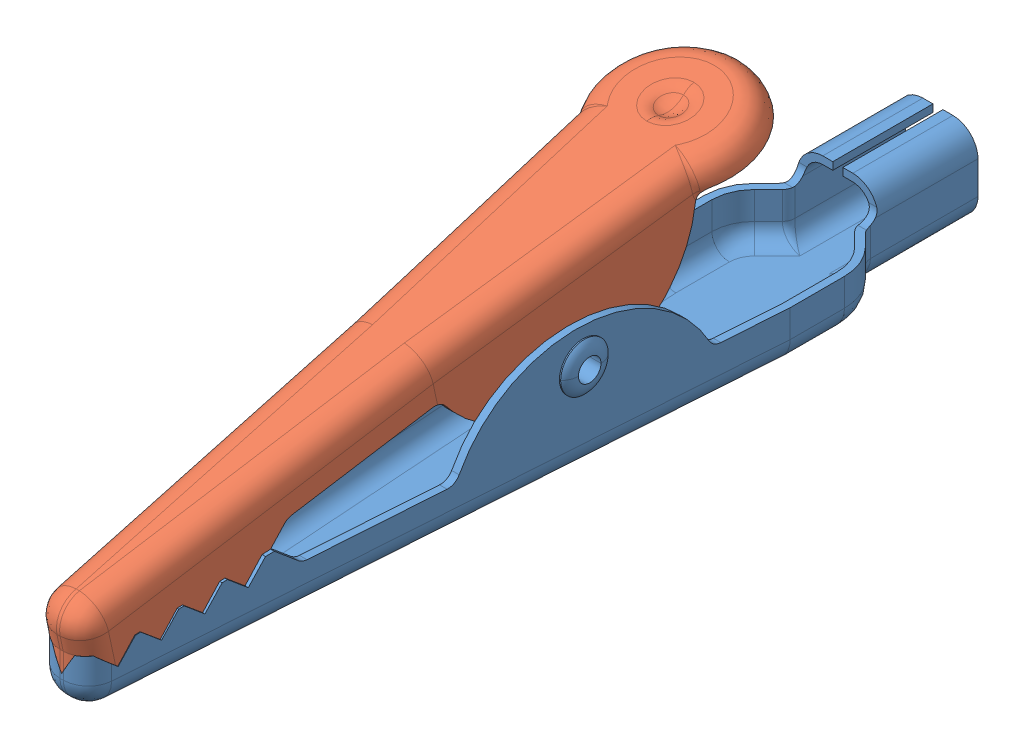
SolidWorks assembly Crocodile Clip.STEP, configuration Default. Lengths in mm.
Overall size (5.6 9.22 35.15).
2 component instances, 2 part files, 0 mates.
Components (placement in the parent):
- Crocodile clip_01.STEP-1: Crocodile clip_01.STEP [Default] x (-1 0 0) z (0 0 -1) size (5.6 6.69 35)
- Crocodile clip_02.STEP-1: Crocodile clip_02.STEP [Default] at (0 -0.0209 0) x (-1 0 0) z (0 0 -1) size (5.6 9.22 27.41)
